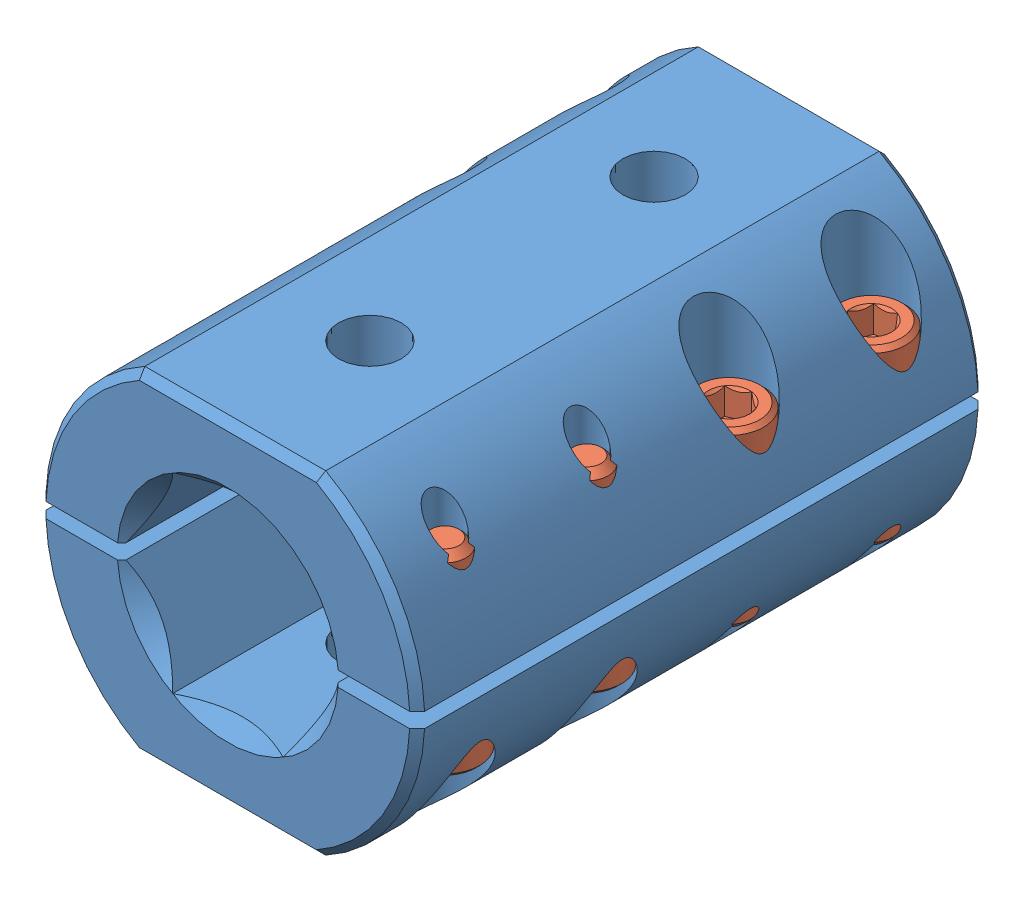
SolidWorks assembly 217-4008-STEP-20140807, configuration Default. Lengths in mm.
Overall size (25.76 22.32 39.56).
10 component instances, 2 part files, 0 mates.
Components (placement in the parent):
- 217-4008-001 Rev1-1: 217-4008-001 Rev1 [Default] at origin size (25.38 10.66 39.56)
- 217-4008-001 Rev1-2: 217-4008-001 Rev1 [Default] x (1 0 0) z (0 0 -1) size (25.38 10.66 39.56)
- 217-4008-002 Rev1_91251A108-1: 217-4008-002 Rev1_91251A108 [Default] at (9.7928 7.025 4.7625) x (0.994016 0 -0.109231) z (0 1 0) size (4.65 4.65 12.51)
- 217-4008-002 Rev1_91251A108-2: 217-4008-002 Rev1_91251A108 [Default] at (9.7928 7.025 14.2875) x (-0.765668 0 -0.643235) z (0 1 0) size (4.65 4.65 12.51)
- 217-4008-002 Rev1_91251A108-3: 217-4008-002 Rev1_91251A108 [Default] at (-9.7928 7.025 14.2875) x (-0.114094 0 0.99347) z (0 1 0) size (4.65 4.65 12.51)
- 217-4008-002 Rev1_91251A108-4: 217-4008-002 Rev1_91251A108 [Default] at (-9.7928 7.025 4.7625) x (0.20346 0 0.979083) z (0 1 0) size (4.65 4.65 12.51)
- 217-4008-002 Rev1_91251A108-5: 217-4008-002 Rev1_91251A108 [Default] at (-9.7928 -7.025 -4.7625) x (0.20346 0 -0.979083) z (0 -1 0) size (4.65 4.65 12.51)
- 217-4008-002 Rev1_91251A108-6: 217-4008-002 Rev1_91251A108 [Default] at (-9.7928 -7.025 -14.2875) x (-0.114094 0 -0.99347) z (0 -1 0) size (4.65 4.65 12.51)
- 217-4008-002 Rev1_91251A108-7: 217-4008-002 Rev1_91251A108 [Default] at (9.7928 -7.025 -14.2875) x (-0.765668 0 0.643235) z (0 -1 0) size (4.65 4.65 12.51)
- 217-4008-002 Rev1_91251A108-8: 217-4008-002 Rev1_91251A108 [Default] at (9.7928 -7.025 -4.7625) x (0.994016 0 0.109231) z (0 -1 0) size (4.65 4.65 12.51)
